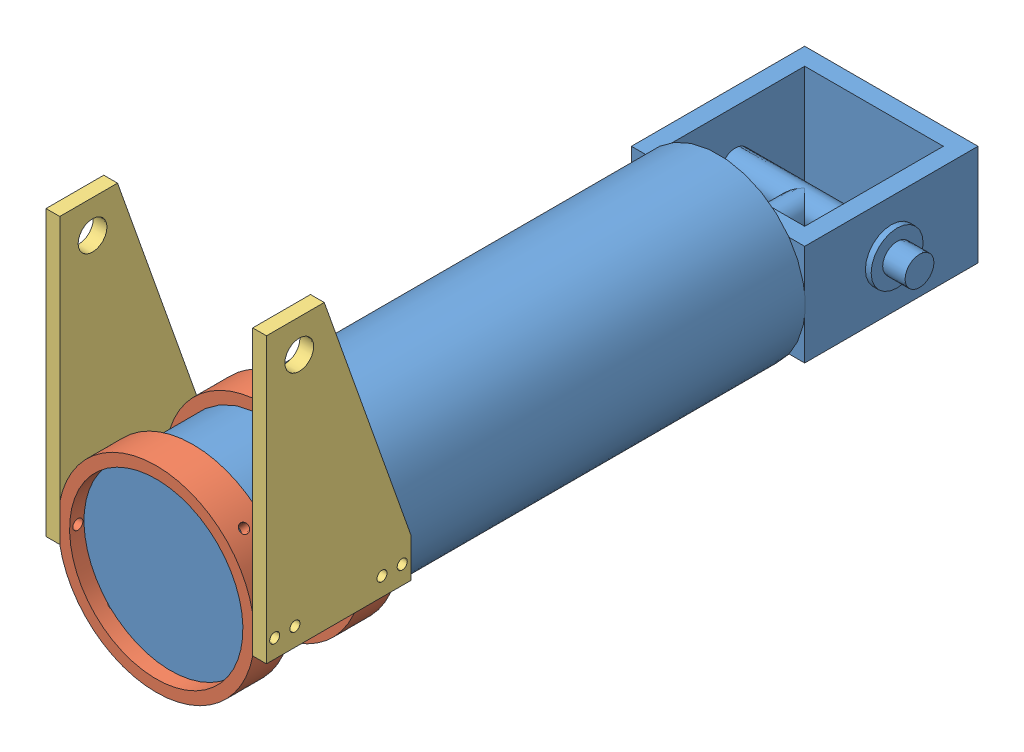
SolidWorks assembly EslabonHorizontal_Inv, configuration Predeterminado. Lengths in mm.
Overall size (96.17 140.08 254.5).
5 component instances, 3 part files, 10 mates.
Components (placement in the parent):
- EslabonSimplificado-1: EslabonSimplificado [Predeterminado] at origin size (79.5 60.33 249.5)
- SujeccionMotorV2-1: SujeccionMotorV2 [Predeterminado] at (0 0 181) x (0.707107 0.707107 0) z (0 0 1) size (68 68 12.7)
- Soporte-1: Soporte [Predeterminado] at (33.4018 -6.35 224.5) x (0 0 1) z (1 0 0) size (50 98.35 4.76)
- SujeccionMotorV2-2: SujeccionMotorV2 [Predeterminado] at (0 0 218.15) x (0.707107 0.707107 0) z (0 0 1) size (68 68 12.7)
- Soporte-2: Soporte [Predeterminado] at (-38.1643 -6.35 224.5) x (0 0 1) z (1 0 0) size (50 98.35 4.76)
Mates (geometry in assembly coordinates):
- Concéntrica2: concentric aligned: cylinder of EslabonSimplificado-1 through (0 0 30) axis (0 0 1) radius 30.165; cylinder of SujeccionMotorV2-2 through (0 0 211.8) axis (0 0 1) radius 30
- Concéntrica3: concentric aligned: cylinder of EslabonSimplificado-1 through (0 0 30) axis (0 0 1) radius 30.165; cylinder of SujeccionMotorV2-1 through (0 0 174.65) axis (0 0 1) radius 30
- Distancia1: distance = 5 mm aligned: plane of EslabonSimplificado-1 through (0 0 219.5) normal (0 0 1); plane of SujeccionMotorV2-2 through (0 0 224.5) normal (0 0 1)
- Paralelo1: parallel aligned: plane of EslabonSimplificado-1 through (30 -17.5 -30) normal (1 0 0); plane of SujeccionMotorV2-1 through (33.4018 6.35 174.65) normal (1 0 0)
- Coincidente3: coincident anti-aligned: plane of Soporte-1 through (33.4018 -6.35 224.5) normal (-1 0 0); plane of SujeccionMotorV2-2 through (33.4018 6.35 211.8) normal (1 0 0)
- Concéntrica4: concentric aligned: cylinder of Soporte-1 through (38.1643 0 221.65) axis (-1 0 0) radius 1.75; cylinder of SujeccionMotorV2-2 through (48.0833 0 221.65) axis (-1 0 0) radius 1.75
- Concéntrica5: concentric aligned: cylinder of SujeccionMotorV2-1 through (48.0833 0 177.5) axis (-1 0 0) radius 1.75; cylinder of Soporte-1 through (38.1643 0 177.5) axis (-1 0 0) radius 1.75
- Coincidente5: coincident: plane of SujeccionMotorV2-2 through (-33.4018 6.35 211.8) normal (-1 0 0); plane of Soporte-2 through (-31.221 -22.5589 204.449) normal (1 0 0)
- Concéntrica6: concentric: cylinder of SujeccionMotorV2-2 through (48.0833 0 221.65) axis (-1 0 0) radius 1.75; cylinder of Soporte-2 through (-31.221 -17.7092 209.4415) axis (-1 0 0) radius 1.75
- Concéntrica7: concentric aligned: cylinder of SujeccionMotorV2-1 through (48.0833 0 177.5) axis (-1 0 0) radius 1.75; cylinder of Soporte-2 through (-31.221 23.7789 194.3431) axis (-1 0 0) radius 1.75
